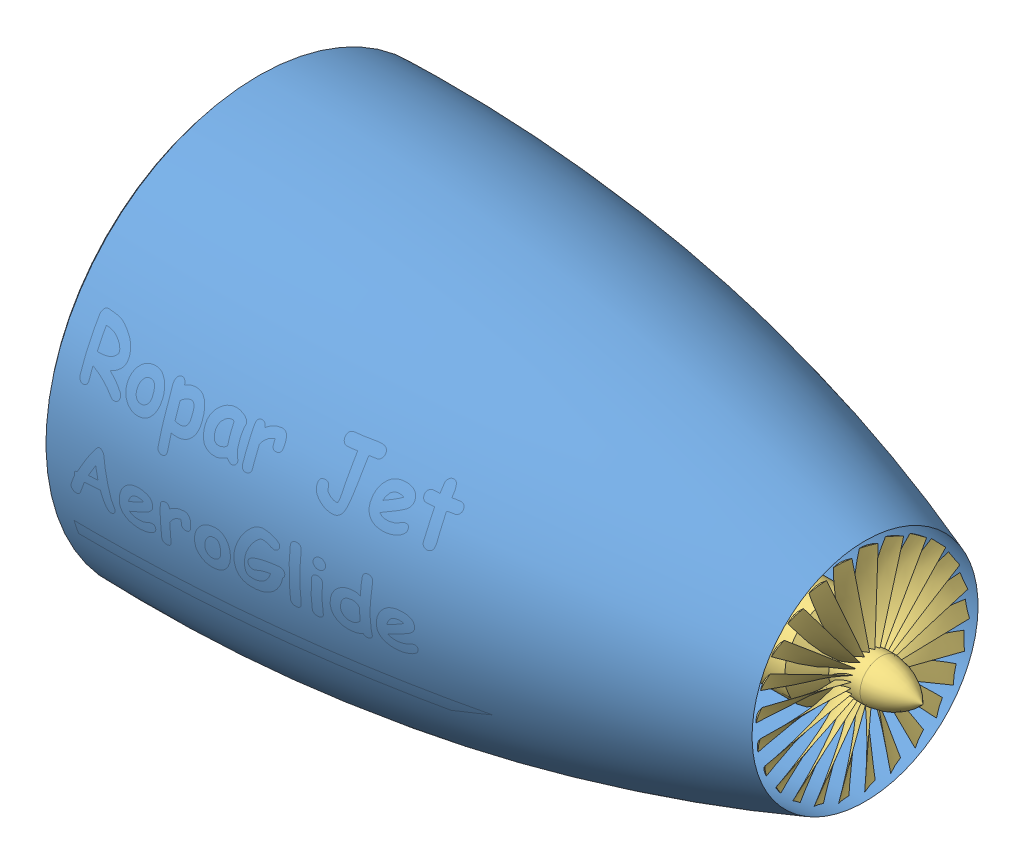
SolidWorks assembly Assem1, configuration Default. Lengths in mm.
Overall size (768.23 413.17 413.17).
3 component instances, 3 part files, 13 mates.
Components (placement in the parent):
- 3 housing-1: 3 housing [Default] at (-29.1091 305.1434 429.3914) size (585.87 413.17 413.17)
- 1 propeller-1: 1 propeller [Default] at (-162.0067 305.1434 429.3914) x (0 -0.999986 -0.005378) z (-1 0 0) size (325.11 326.67 166)
- 2 SHAFT-1: 2 SHAFT [Default] at (-34.0067 305.1434 429.3914) x (1 0 0) z (0 0.999986 0.005378) size (640.23 200.1 200.49)
Mates (geometry in assembly coordinates):
- Concentric11: concentric anti-aligned: cylinder of 1 propeller-1 through (-34.0067 305.1434 429.3914) axis (1 0 0) radius 20; cylinder of 2 SHAFT-1 through (-34.0067 305.1434 429.3914) axis (-1 0 0) radius 20
- Coincident6: coincident anti-aligned: plane of 1 propeller-1 through (-34.0067 305.1434 429.3914) normal (1 0 0); circle of 2 SHAFT-1
- Concentric12: concentric aligned: cylinder of 3 housing-1 through (-29.1091 305.1434 429.3914) axis (-1 0 0) radius 180; cylinder of 2 SHAFT-1 through (-34.0067 305.1434 429.3914) axis (-1 0 0) radius 43.4377
- Concentric13: concentric aligned: cylinder of 3 housing-1 through (-29.1091 305.1434 429.3914) axis (-1 0 0) radius 180; circle of 2 SHAFT-1
- Concentric14: concentric aligned: circle of 3 housing-1; circle of 2 SHAFT-1
- Concentric15: concentric aligned: circle of 3 housing-1; circle of 2 SHAFT-1
- Concentric16: concentric aligned: circle of 3 housing-1; circle of 2 SHAFT-1
- Concentric17: concentric aligned: cylinder of 3 housing-1 through (-29.1091 305.1434 429.3914) axis (-1 0 0) radius 180; cone of 1 propeller-1 through (-46.8443 305.1434 429.3914) axis (-1 0 0)
- Concentric18: concentric aligned: circle of 3 housing-1; circle of 1 propeller-1
- Coincident11: coincident anti-aligned: plane of 1 propeller-1 through (-162.0067 305.1434 429.3914) normal (0 -0.005378 0.999986); plane of 2 SHAFT-1 through (-34.0067 305.1434 429.3914) normal (0 0.005378 -0.999986)
- Concentric21: concentric aligned: circle of 3 housing-1; circle of 1 propeller-1
- Concentric22: concentric aligned: circle of 3 housing-1; circle of 2 SHAFT-1
- Lock1: lock: unknown of 3 housing-1; unknown of 1 propeller-1
